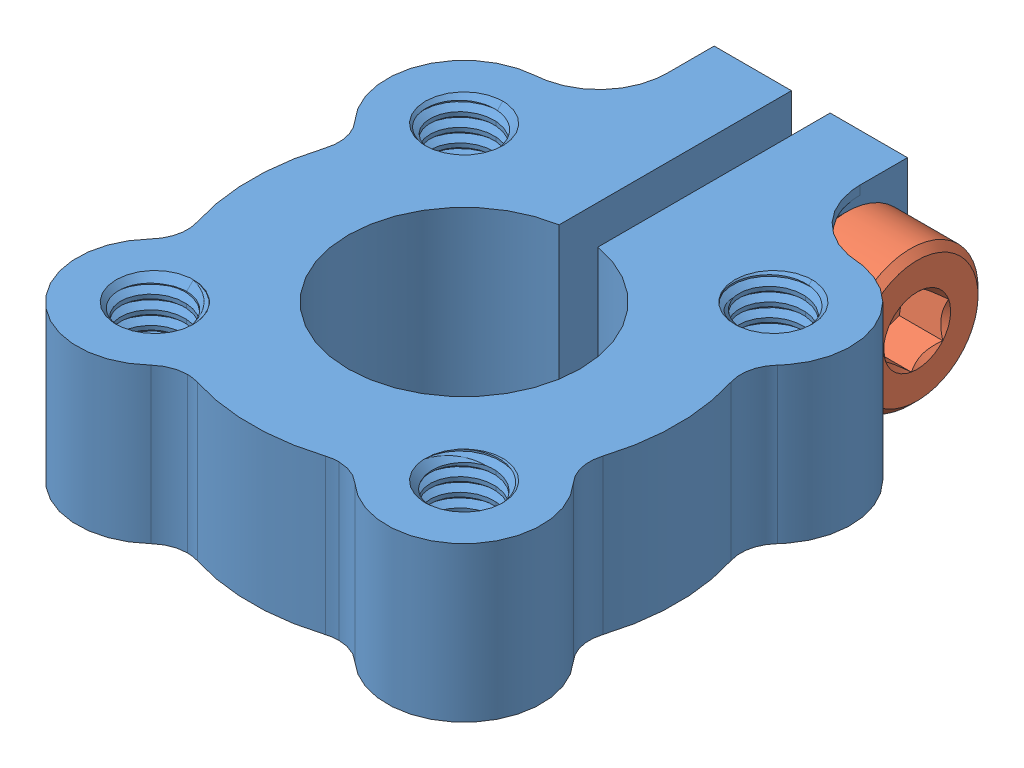
SolidWorks assembly 12mm Clamping Hub 1301-0016-0012, configuration Default. Lengths in mm.
Overall size (24 9.05 30.49).
2 component instances, 2 part files, 0 mates.
Components (placement in the parent):
- 1301-0016-0012.STEP-1: 1301-0016-0012.STEP [Default] at (19.3408 -18.3786 2.1055) size (24 9 29.94)
- 2800-0004-0010_90128A207.STEP-1: 2800-0004-0010_90128A207.STEP [Default] at (14.3408 -13.3786 -12.3298) x (0 -0.173761 -0.984788) z (-1 0 0) size (7 7 14.01)
